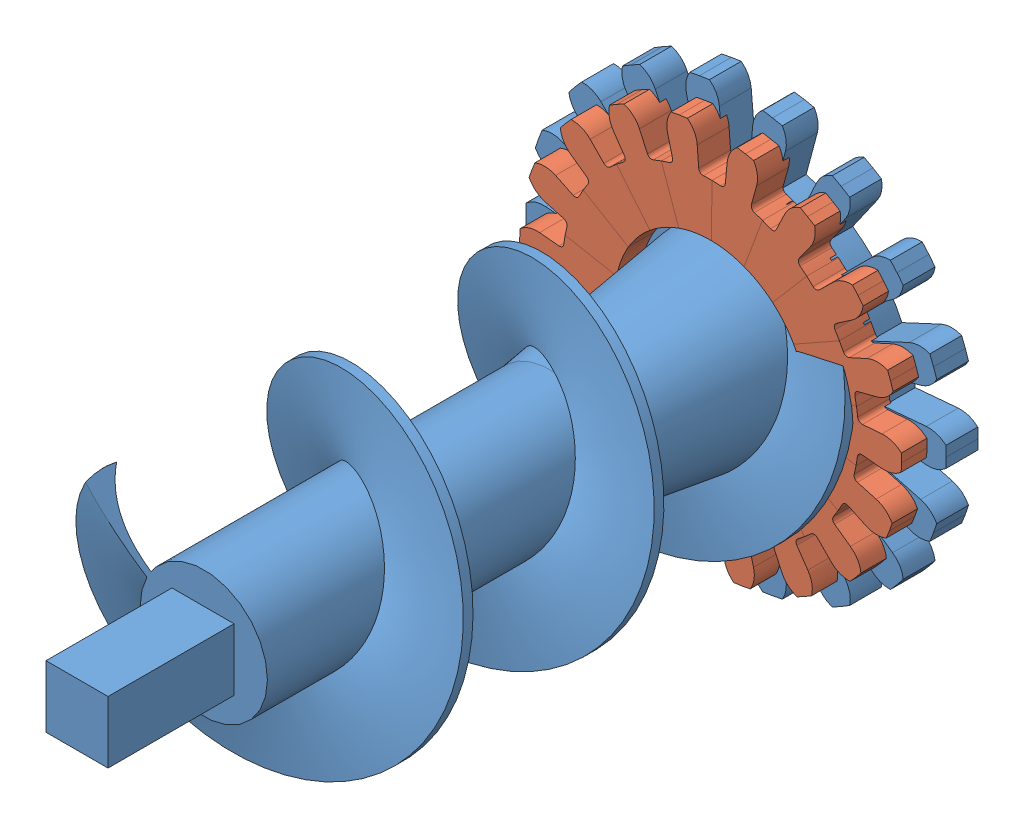
SolidWorks assembly Assemblage vis engrenage, configuration Défaut. Lengths in mm.
Overall size (60.55 60.04 360).
2 component instances, 2 part files, 2 mates.
Components (placement in the parent):
- P3 vis sans fin-1: P3 vis sans fin [Défaut] at (-46.3014 16.7226 -180) size (66.06 65.53 360)
- Engrenage haut de vis-1: Engrenage haut de vis [Défaut] at (-46.3014 16.7226 -174.65) x (0.999957 -0.009284 0) z (0 0 1) size (60 59.49 5)
Mates (geometry in assembly coordinates):
- Coaxiale1: concentric anti-aligned: cone of P3 vis sans fin-1 through (-46.3014 16.7226 -180) axis (0 0 1); cylinder of Engrenage haut de vis-1 through (-46.3014 16.7226 -169.65) axis (0 0 -1) radius 15
- Coïncidente1: coincident aligned: plane of P3 vis sans fin-1 through (-46.3014 16.7226 -174.65) normal (0 0 -1); plane of Engrenage haut de vis-1 through (-46.3014 16.7226 -174.65) normal (0 0 -1)
